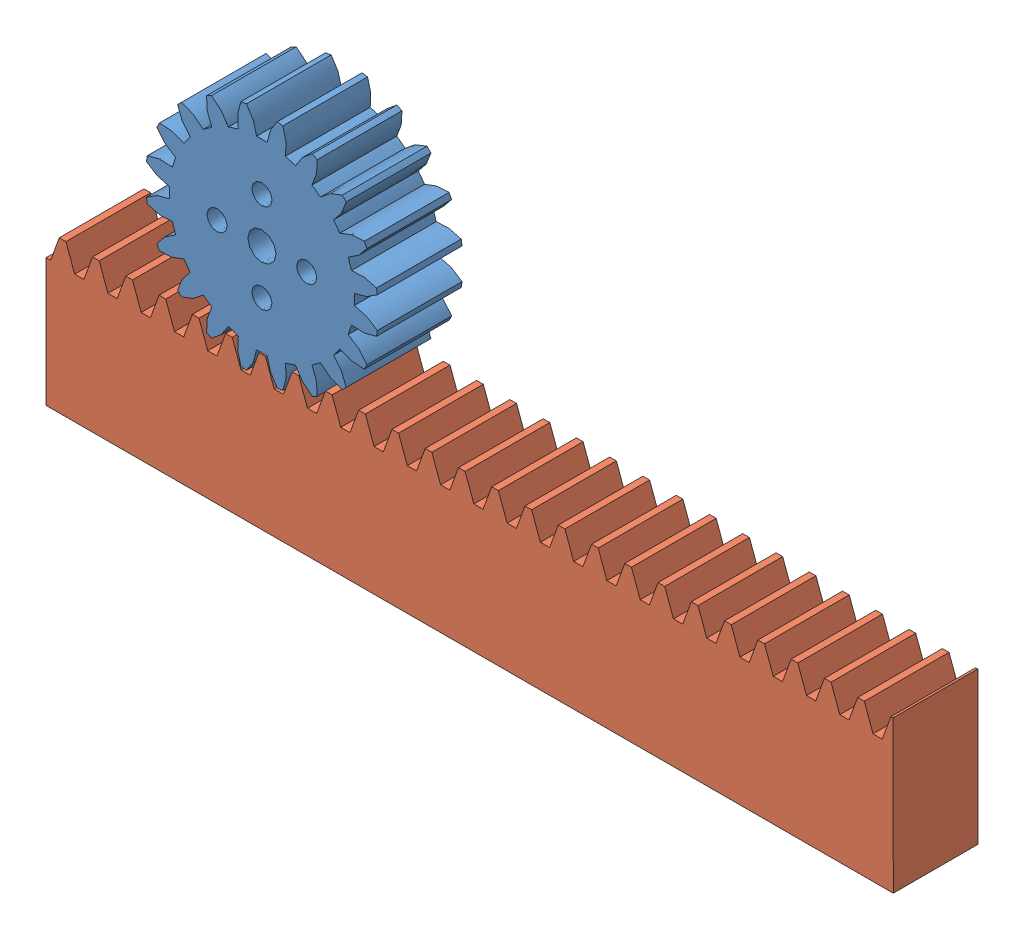
SolidWorks assembly gear&rack, configuration Default. Lengths in mm.
Overall size (123.2 51.19 12).
2 component instances, 2 part files, 5 mates.
Components (placement in the parent):
- ISO - Spur gear 1.5M 20T 20PA 12FW ---S20A75H50L4.0N-1: ISO - Spur gear 1.5M 20T 20PA 12FW ---S20A75H50L4.0N [ISO - Spur gear 1.5M 20T 20PA 12FW ---S20A75H50L4.0N] x (0 0 1) z (-1 0 0) size (12 32.71 32.71)
- ISO - Rack-spur - rectangular 1.5M 20PA 12FW 20PH 120L---SAll-2: ISO - Rack-spur - rectangular 1.5M 20PA 12FW 20PH 120L---SAll [ISO - Rack-spur - rectangular 1.5M 20PA 12FW 20PH 120L---SAll] at (-30.5576 -34.8407 12) x (0.999999 0.001395 0) z (0 0 1) size (120 21.5 12)
Mates (geometry in assembly coordinates):
- Concentric1: concentric: cylinder of ISO - Spur gear 1.5M 20T 20PA 12FW ---S20A75H50L4.0N-1 through (0 0 50.0001) axis (0 0 -1) radius 2; line of assembly
- Coincident2: coincident: plane of ISO - Spur gear 1.5M 20T 20PA 12FW ---S20A75H50L4.0N-1 through (0 0 0) normal (0 0 -1); plane of assembly through (0 0 0) normal (0 0 1)
- Coincident4: coincident: plane of ISO - Rack-spur - rectangular 1.5M 20PA 12FW 20PH 120L---SAll-2 through (-49.4915 -13.533 0) normal (0 0 -1); plane of assembly through (0 0 0) normal (0 0 1)
- Distance3: distance = 34.798 mm: line of assembly; plane of ISO - Rack-spur - rectangular 1.5M 20PA 12FW 20PH 120L---SAll-2 through (-30.5576 -34.8407 0) normal (0.001395 -0.999999 0)
- RackPinionMate2: rack pinion = 12 mm: line of ISO - Rack-spur - rectangular 1.5M 20PA 12FW 20PH 120L---SAll-2 through (-47.6085 -13.5241 12) axis (0 0 -1); circle of ISO - Spur gear 1.5M 20T 20PA 12FW ---S20A75H50L4.0N-1
